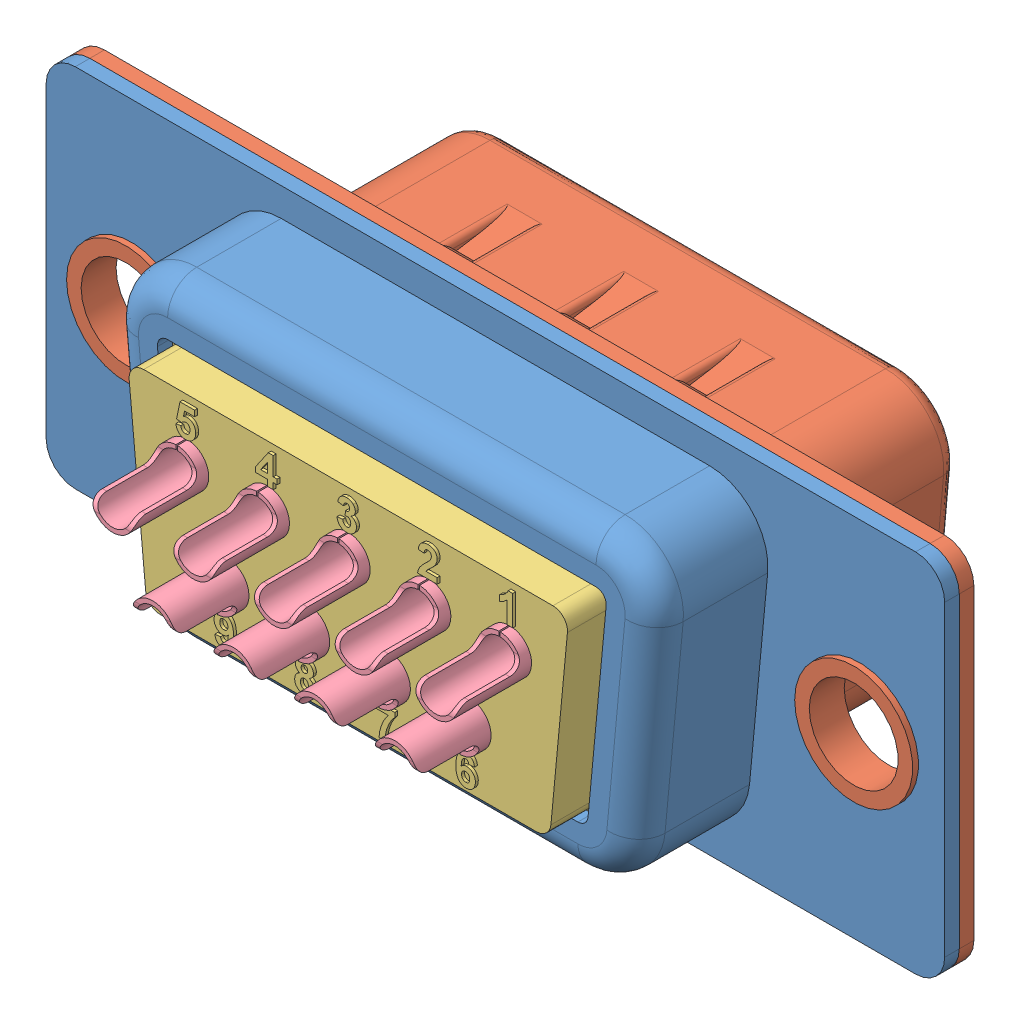
SolidWorks assembly Assem dt, configuration Default. Lengths in mm.
Overall size (30.84 17.69 14.7).
12 component instances, 4 part files, 35 mates.
Components (placement in the parent):
- D-T -1-1: D-T -1 [Default] at (15.4076 17.3206 20.7832) size (30.84 17.69 4.4)
- D-T-1: D-T [Default] at (15.4076 17.3206 20.7832) x (-1 0 0) z (0 0 -1) size (30.84 12.55 7.3)
- D-T -2-1: D-T -2 [Default] at (15.4076 17.3206 24.5832) x (-1 0 0) z (0 0 -1) size (16.3 8.2 5.75)
- D-t pin-1: D-t pin [Default] at (9.8676 18.7406 15.6832) size (1.5 1.51 13.2)
- D-t pin-2: D-t pin [Default] at (12.6376 18.7406 15.6832) size (1.5 1.51 13.2)
- D-t pin-3: D-t pin [Default] at (14.0182 15.9006 15.6832) x (-1 0 0) z (0 0 1) size (1.5 1.51 13.2)
- D-t pin-4: D-t pin [Default] at (11.2482 15.9006 15.6832) x (-1 0 0) z (0 0 1) size (1.5 1.51 13.2)
- D-t pin-5: D-t pin [Default] at (18.1776 18.7406 15.6832) size (1.5 1.51 13.2)
- D-t pin-6: D-t pin [Default] at (15.4076 18.7406 15.6832) size (1.5 1.51 13.2)
- D-t pin-7: D-t pin [Default] at (16.7882 15.9006 15.6832) x (-1 0 0) z (0 0 1) size (1.5 1.51 13.2)
- D-t pin-8: D-t pin [Default] at (19.5582 15.9006 15.6832) x (-1 0 0) z (0 0 1) size (1.5 1.51 13.2)
- D-t pin-9: D-t pin [Default] at (20.9476 18.7406 15.6832) size (1.5 1.51 13.2)
Mates (geometry in assembly coordinates):
- Coincident1: coincident anti-aligned: plane of D-T -1-1 through (29.8276 22.5956 20.7832) normal (0 0 -1); plane of D-T-1 through (0.9876 22.5956 20.7832) normal (0 0 1)
- Coincident2: coincident aligned: plane of D-T -1-1 through (30.8276 22.5956 21.2832) normal (1 0 0); plane of D-T-1 through (30.8276 22.5956 20.2832) normal (1 0 0)
- Coincident3: coincident aligned: plane of D-T -1-1 through (0.9876 23.5956 21.2832) normal (0 1 0); plane of D-T-1 through (29.8276 23.5956 20.2832) normal (0 1 0)
- Coincident4: coincident anti-aligned: plane of D-T-1 through (0.9876 22.5956 20.7832) normal (0 0 1); plane of D-T -2-1 through (8.0551 20.6206 20.7832) normal (0 0 -1)
- Width1: width anti-aligned: plane of D-T -2-1 through (8.0551 21.4206 20.7832) normal (0 1 0); plane of D-T -1-1 through (22.1374 13.2206 20.7832) normal (0 -1 0); plane of D-T -2-1 through (22.76 21.4706 2.3982) normal (0 -1 0); plane of D-T -1-1 through (8.6778 13.1706 2.3982) normal (0 1 0)
- Width2: width anti-aligned: plane of D-T -2-1 through (23.5565 20.5455 20.7832) normal (0.99558 -0.093923 0); plane of D-T -1-1 through (7.8813 13.9455 20.7832) normal (-0.99558 -0.093923 0); plane of D-T -2-1 through (22.9836 13.9408 2.3982) normal (-0.99558 0.093923 0); plane of D-T -1-1 through (7.2089 20.5408 2.3982) normal (0.99558 0.093923 0)
- Concentric2: concentric anti-aligned: circle of D-T -2-1; cylinder of D-t pin-1 through (9.8676 18.7406 20.7832) axis (0 0 -1) radius 0.5
- Coincident6: coincident anti-aligned: plane of D-T -2-1 through (9.8676 18.7406 22.5332) normal (0 0 1); plane of D-t pin-1 through (9.8676 18.7406 22.5332) normal (0 0 -1)
- Concentric3: concentric aligned: cylinder of D-T -2-1 through (12.6376 18.7406 28.4545) axis (0 0 -1) radius 0.75; cylinder of D-t pin-2 through (12.6376 18.7406 20.7832) axis (0 0 -1) radius 0.5
- Concentric4: concentric aligned: cylinder of D-T -2-1 through (15.4076 18.7406 28.4545) axis (0 0 -1) radius 0.75; cylinder of D-t pin-6 through (15.4076 18.7406 20.7832) axis (0 0 -1) radius 0.5
- Concentric5: concentric aligned: cylinder of D-T -2-1 through (18.1776 18.7406 28.4545) axis (0 0 -1) radius 0.75; cylinder of D-t pin-5 through (18.1776 18.7406 20.7832) axis (0 0 -1) radius 0.5
- Concentric6: concentric aligned: cylinder of D-T -2-1 through (20.9476 18.7406 28.4545) axis (0 0 -1) radius 0.75; cylinder of D-t pin-9 through (20.9476 18.7406 20.7832) axis (0 0 -1) radius 0.5
- Coincident8: coincident anti-aligned: plane of D-T -2-1 through (12.6376 18.7406 22.5332) normal (0 0 1); plane of D-t pin-2 through (12.6376 18.7406 22.5332) normal (0 0 -1)
- Coincident9: coincident anti-aligned: plane of D-T -2-1 through (15.4076 18.7406 22.5332) normal (0 0 1); plane of D-t pin-6 through (15.4076 18.7406 22.5332) normal (0 0 -1)
- Coincident10: coincident anti-aligned: plane of D-T -2-1 through (18.1776 18.7406 22.5332) normal (0 0 1); plane of D-t pin-5 through (18.1776 18.7406 22.5332) normal (0 0 -1)
- Coincident11: coincident anti-aligned: plane of D-T -2-1 through (20.9476 18.7406 22.5332) normal (0 0 1); plane of D-t pin-9 through (20.9476 18.7406 22.5332) normal (0 0 -1)
- Concentric7: concentric aligned: cylinder of D-T -2-1 through (11.2482 15.9006 28.4545) axis (0 0 -1) radius 0.75; cylinder of D-t pin-4 through (11.2482 15.9006 20.7832) axis (0 0 -1) radius 0.5
- Concentric8: concentric aligned: cylinder of D-T -2-1 through (14.0182 15.9006 28.4545) axis (0 0 -1) radius 0.75; cylinder of D-t pin-3 through (14.0182 15.9006 20.7832) axis (0 0 -1) radius 0.5
- Concentric9: concentric aligned: cylinder of D-T -2-1 through (16.7882 15.9006 28.4545) axis (0 0 -1) radius 0.75; cylinder of D-t pin-7 through (16.7882 15.9006 20.7832) axis (0 0 -1) radius 0.5
- Concentric10: concentric aligned: cylinder of D-T -2-1 through (19.5582 15.9006 28.4545) axis (0 0 -1) radius 0.75; cylinder of D-t pin-8 through (19.5582 15.9006 20.7832) axis (0 0 -1) radius 0.5
- Coincident12: coincident anti-aligned: plane of D-T -2-1 through (19.5582 15.9006 22.5332) normal (0 0 1); plane of D-t pin-8 through (19.5582 15.9006 22.5332) normal (0 0 -1)
- Coincident13: coincident anti-aligned: plane of D-T -2-1 through (16.7882 15.9006 22.5332) normal (0 0 1); plane of D-t pin-7 through (16.7882 15.9006 22.5332) normal (0 0 -1)
- Coincident14: coincident anti-aligned: plane of D-T -2-1 through (14.0182 15.9006 22.5332) normal (0 0 1); plane of D-t pin-3 through (14.0182 15.9006 22.5332) normal (0 0 -1)
- Coincident15: coincident anti-aligned: plane of D-T -2-1 through (11.2482 15.9006 22.5332) normal (0 0 1); plane of D-t pin-4 through (11.2482 15.9006 22.5332) normal (0 0 -1)
- Parallel2: parallel aligned: plane of D-t pin-1 through (9.8426 19.24 16.1832) normal (1 0 0); plane of assembly through (0 0 0) normal (1 0 0)
- Parallel3: parallel aligned: plane of D-t pin-2 through (12.6126 19.24 16.1832) normal (1 0 0); plane of assembly through (0 0 0) normal (1 0 0)
- Parallel4: parallel aligned: plane of D-t pin-6 through (15.3826 19.24 16.1832) normal (1 0 0); plane of assembly through (0 0 0) normal (1 0 0)
- Parallel5: parallel aligned: plane of D-t pin-5 through (18.1526 19.24 16.1832) normal (1 0 0); plane of assembly through (0 0 0) normal (1 0 0)
- Parallel6: parallel aligned: plane of D-t pin-9 through (20.9226 19.24 16.1832) normal (1 0 0); plane of assembly through (0 0 0) normal (1 0 0)
- Parallel7: parallel anti-aligned: plane of D-t pin-8 through (19.5832 15.4013 16.1832) normal (-1 0 0); plane of assembly through (0 0 0) normal (1 0 0)
- Parallel8: parallel anti-aligned: plane of D-t pin-7 through (16.8132 15.4013 16.1832) normal (-1 0 0); plane of assembly through (0 0 0) normal (1 0 0)
- Parallel9: parallel anti-aligned: plane of D-t pin-3 through (14.0432 15.4013 16.1832) normal (-1 0 0); plane of assembly through (0 0 0) normal (1 0 0)
- Parallel10: parallel anti-aligned: plane of D-t pin-4 through (11.2732 15.4013 16.1832) normal (-1 0 0); plane of assembly through (0 0 0) normal (1 0 0)
- Concentric11: concentric aligned: circle of D-T-1; cylinder of ? through (2.9126 17.3206 9.2968) axis (0 0 1) radius 1.525
- Concentric12: concentric anti-aligned: cylinder of D-T-1 through (27.9026 17.3206 25.0966) axis (0 0 -1) radius 1.525; cylinder of ? through (27.9026 17.3206 9.2968) axis (0 0 1) radius 1.525
